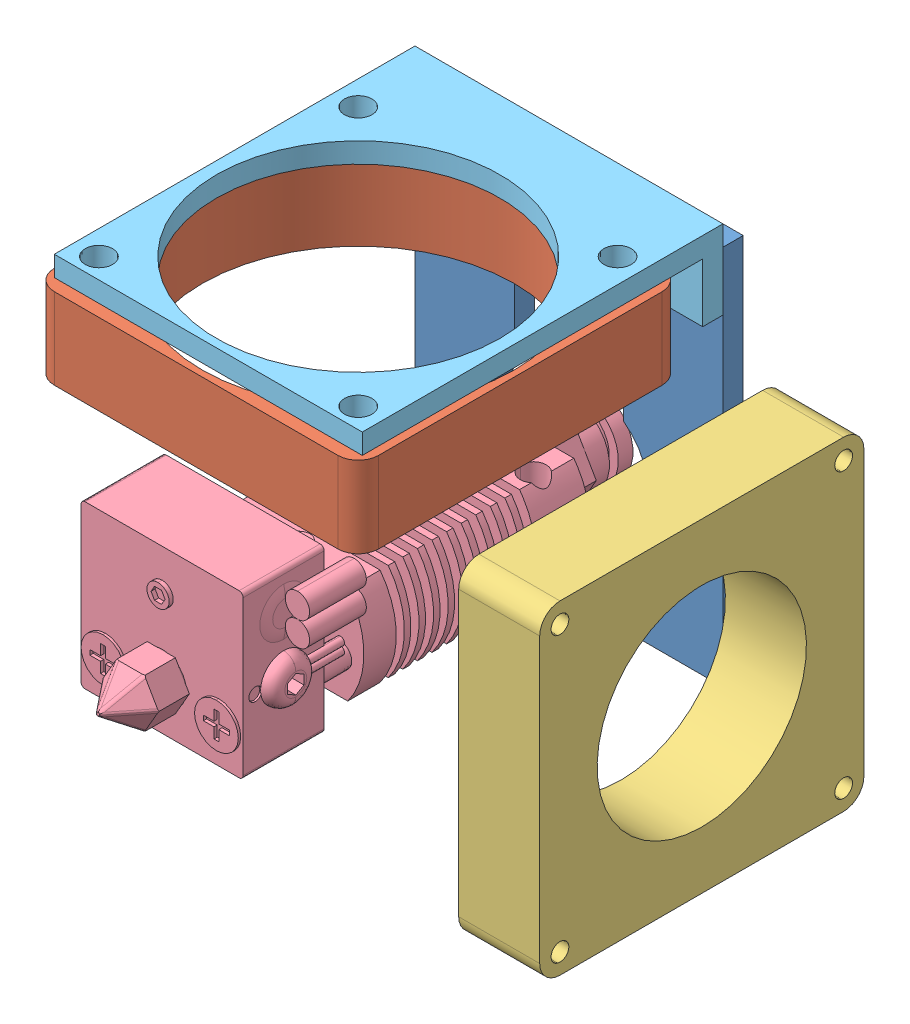
SolidWorks assembly Assembly, configuration Default. Lengths in mm.
Overall size (56.59 52.65 61).
5 component instances, 5 part files, 13 mates.
Components (placement in the parent):
- Heater holder-1: Heater holder [Default] at (12.5967 24.468 30.4773) size (38 47 16.5)
- Cooling Fan A-1: Cooling Fan A [Default] at (12.5967 37.968 58.9773) x (-1 0 0) z (0 1 0) size (40 40 10)
- Cooling Fan B-1: Cooling Fan B [Default] at (49.1883 17.8188 53.1771) x (0 1 0) z (-1 0 0) size (40 40 10)
- MK8 Hotend.step-1: MK8 Hotend.step [Default] at (12.6967 21.718 83.2773) x (-1 0 0) z (0 -1 0) size (23.9 61 20)
- Motor A Support-1: Motor A Support [Default] at (12.5967 44.343 32.9773) x (1 0 0) z (0 -1 0) size (38 44.5 9.75)
Mates (geometry in assembly coordinates):
- Parallel6: parallel aligned: plane of Heater holder-1 through (-6.4033 47.968 32.9773) normal (0 1 0); plane of Cooling Fan B-1 through (39.1883 37.8188 35.6771) normal (0 1 0)
- Parallel7: parallel aligned: plane of Heater holder-1 through (-6.4033 47.968 32.9773) normal (-1 0 0); plane of Cooling Fan A-1 through (-7.4033 47.968 76.4773) normal (-1 0 0)
- Parallel8: parallel aligned: plane of Heater holder-1 through (12.5967 24.468 30.4773) normal (0 0 -1); plane of Cooling Fan A-1 through (30.0967 47.968 38.9773) normal (0 0 -1)
- Parallel9: parallel aligned: plane of Heater holder-1 through (12.5967 24.468 30.4773) normal (0 0 -1); plane of Cooling Fan B-1 through (39.1883 0.3188 33.1771) normal (0 0 -1)
- Concentric74: concentric aligned: cylinder of Heater holder-1 through (3.4967 44.568 32.9773) axis (0 0 -1) radius 1.375; cylinder of Motor A Support-1 through (3.4967 44.568 35.4773) axis (0 0 -1) radius 1.375
- Concentric75: concentric aligned: cylinder of Heater holder-1 through (21.6967 44.568 32.9773) axis (0 0 -1) radius 1.375; cylinder of Motor A Support-1 through (21.6967 44.568 35.4773) axis (0 0 -1) radius 1.375
- Coincident55: coincident anti-aligned: plane of Heater holder-1 through (12.5967 24.468 32.9773) normal (0 0 1); plane of Motor A Support-1 through (12.5967 44.343 32.9773) normal (0 0 -1)
- Concentric76: concentric anti-aligned: cylinder of Cooling Fan A-1 through (-3.4033 47.968 74.9773) axis (0 -1 0) radius 2; cylinder of Motor A Support-1 through (-3.4033 40.468 74.9773) axis (0 1 0) radius 1.7
- Concentric77: concentric anti-aligned: cylinder of Cooling Fan A-1 through (28.5967 47.968 42.9773) axis (0 -1 0) radius 2; cylinder of Motor A Support-1 through (28.5967 40.468 42.9773) axis (0 1 0) radius 1.7
- Coincident56: coincident anti-aligned: plane of Cooling Fan A-1 through (-4.9033 47.968 76.4773) normal (0 1 0); plane of Motor A Support-1 through (-6.4033 47.968 77.4773) normal (0 -1 0)
- Concentric78: concentric anti-aligned: circle of Heater holder-1; cylinder of MK8 Hotend.step-1 through (5.6967 3.718 44.4773) axis (0 1 0) radius 1.6
- Parallel10: parallel anti-aligned: plane of Heater holder-1 through (12.5967 24.468 46.9773) normal (0 0 1); plane of MK8 Hotend.step-1 through (34.8381 17.718 40.4773) normal (0 0 -1)
- Coincident57: coincident anti-aligned: plane of Heater holder-1 through (5.8467 11.718 30.4773) normal (0 1 0); plane of MK8 Hotend.step-1 through (34.8381 11.718 40.4773) normal (0 -1 0)
